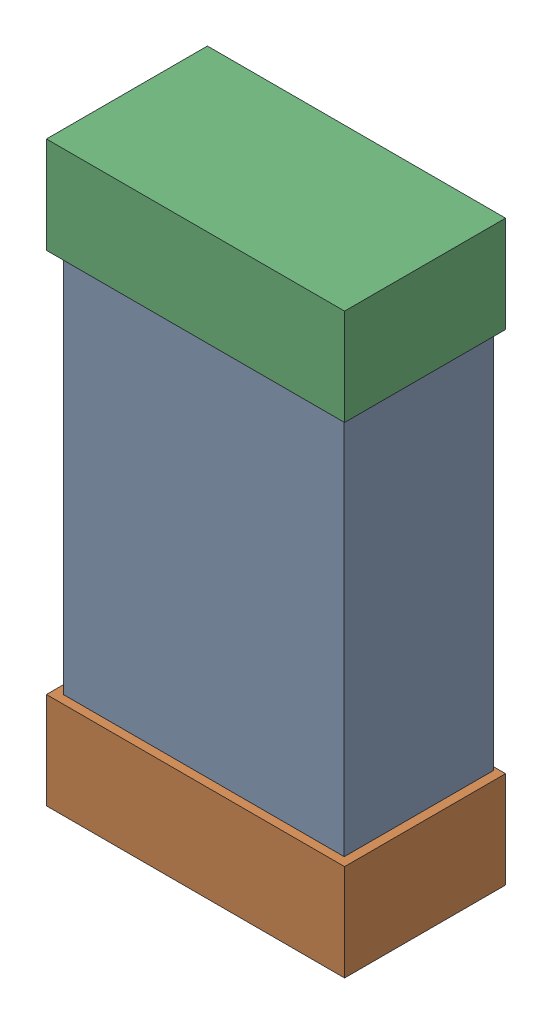
SolidWorks assembly C22, configuration Default. Lengths in mm.
Overall size (0.85 1.65 0.46).
6 component instances, 2 part files, 0 mates.
Components (placement in the parent):
- 432124816_33-1: 432124816_33 [Default] at (20.3451 19.4533 -0.8615) size (0.8 1.5 0.42)
  - Extruded (1)-1: Extruded (1) [Default] at origin size (0.8 1.5 0.42)
- 432138512_66-1: 432138512_66 [Default] at (20.3451 18.7675 -0.8715) size (0.85 0.28 0.46)
  - Extruded-1: Extruded [Default] at origin size (0.85 0.28 0.46)
- 432138512_67-1: 432138512_67 [Default] at (20.3451 20.139 -0.8715) size (0.85 0.28 0.46)
  - Extruded-1: Extruded [Default] at origin size (0.85 0.28 0.46)
